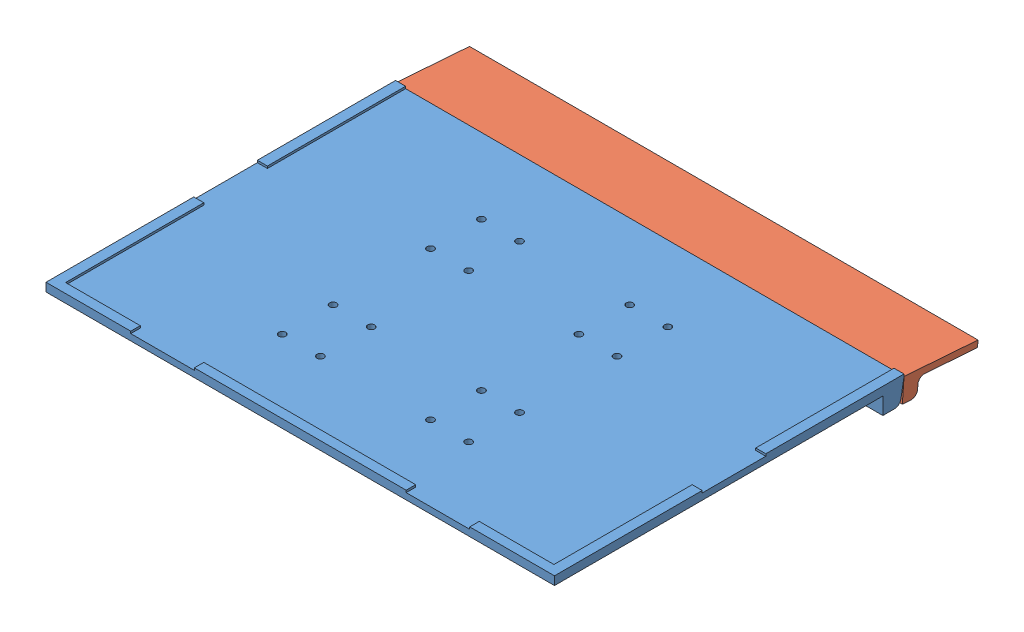
SolidWorks assembly Assem2, configuration Default. Lengths in mm.
Overall size (240 26 199.91).
6 component instances, 3 part files, 14 mates.
Components (placement in the parent):
- Part5-1: Part5 [Default] at (72.3928 131.6928 196.045) size (240 12 165)
- Part6-1: Part6 [Default] at (72.3928 130.4237 96.3106) x (1 0 0) z (0 0.072976 0.997334) size (240 11 35)
- SC8UU-1: SC8UU [Default] at (37.3928 120.1928 161.045) x (0 0 -1) z (1 0 0) size (34 22 30)
- SC8UU-2: SC8UU [Default] at (107.3928 120.1928 231.045) x (0 0 -1) z (1 0 0) size (34 22 30)
- SC8UU-5: SC8UU [Default] at (37.3928 120.1928 231.045) x (0 0 -1) z (1 0 0) size (34 22 30)
- SC8UU-6: SC8UU [Default] at (107.3928 120.1928 161.045) x (0 0 -1) z (1 0 0) size (34 22 30)
Mates (geometry in assembly coordinates):
- Coincident2: coincident aligned: plane of Part5-1 through (192.3928 134.6928 196.045) normal (1 0 0); plane of Part6-1 through (192.3928 132.1386 78.6383) normal (1 0 0)
- Coincident3: coincident aligned: line of Part5-1 through (-42.8572 134.6928 113.545) axis (1 0 0); line of Part6-1 through (-47.6072 134.6928 113.545) axis (1 0 0)
- Coincident5: coincident aligned: circle of Part5-1; cylinder of SC8UU-1 through (28.3928 109.6928 173.045) axis (0 1 0) radius 1.65
- Concentric1: concentric anti-aligned: cylinder of Part5-1 through (46.3928 134.6928 173.045) axis (0 -1 0) radius 1.65; cylinder of SC8UU-1 through (46.3928 109.6928 173.045) axis (0 1 0) radius 1.65
- Coincident6: coincident anti-aligned: plane of Part5-1 through (72.3928 131.6928 196.045) normal (0 -1 0); plane of SC8UU-1 through (52.3928 131.6928 154.045) normal (0 1 0)
- Concentric2: concentric anti-aligned: cylinder of Part5-1 through (116.3928 134.6928 149.045) axis (0 -1 0) radius 1.65; cylinder of SC8UU-6 through (116.3928 109.6928 149.045) axis (0 1 0) radius 1.65
- Concentric3: concentric anti-aligned: cylinder of Part5-1 through (98.3928 134.6928 173.045) axis (0 -1 0) radius 1.65; cylinder of SC8UU-6 through (98.3928 109.6928 173.045) axis (0 1 0) radius 1.65
- Coincident7: coincident anti-aligned: plane of Part5-1 through (72.3928 131.6928 196.045) normal (0 -1 0); plane of SC8UU-6 through (122.3928 131.6928 178.045) normal (0 1 0)
- Concentric4: concentric anti-aligned: cylinder of Part5-1 through (116.3928 134.6928 219.045) axis (0 -1 0) radius 1.65; cylinder of SC8UU-2 through (116.3928 109.6928 219.045) axis (0 1 0) radius 1.65
- Concentric5: concentric anti-aligned: cylinder of Part5-1 through (98.3928 134.6928 219.045) axis (0 -1 0) radius 1.65; cylinder of SC8UU-2 through (98.3928 109.6928 219.045) axis (0 1 0) radius 1.65
- Coincident9: coincident anti-aligned: plane of Part5-1 through (72.3928 131.6928 196.045) normal (0 -1 0); plane of SC8UU-2 through (122.3928 131.6928 224.045) normal (0 1 0)
- Concentric6: concentric anti-aligned: cylinder of Part5-1 through (46.3928 134.6928 219.045) axis (0 -1 0) radius 1.65; cylinder of SC8UU-5 through (46.3928 109.6928 219.045) axis (0 1 0) radius 1.65
- Concentric7: concentric anti-aligned: cylinder of Part5-1 through (28.3928 134.6928 219.045) axis (0 -1 0) radius 1.65; cylinder of SC8UU-5 through (28.3928 109.6928 219.045) axis (0 1 0) radius 1.65
- Coincident10: coincident anti-aligned: plane of Part5-1 through (72.3928 131.6928 196.045) normal (0 -1 0); plane of SC8UU-5 through (52.3928 131.6928 224.045) normal (0 1 0)
